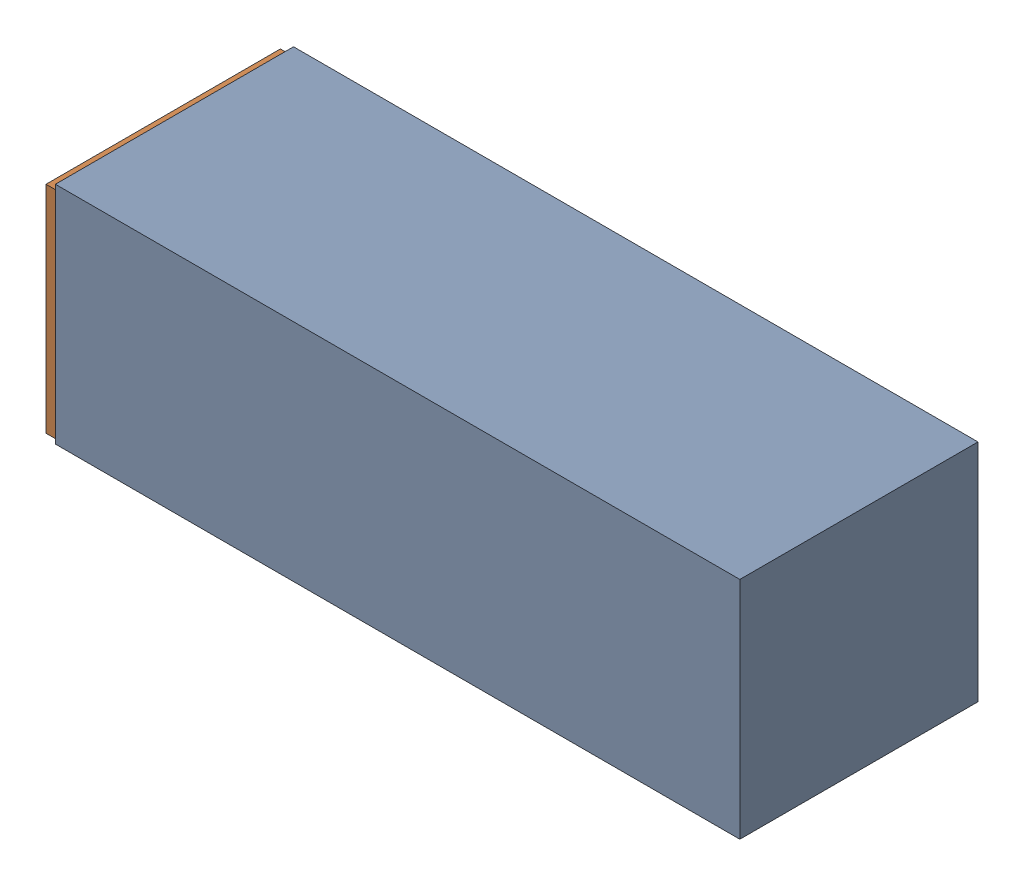
SolidWorks assembly H2, configuration Default. Lengths in mm.
Overall size (46.99 15.24 16.13).
4 component instances, 2 part files, 0 mates.
Components (placement in the parent):
- 407985440-1: 407985440 [Default] at (47.1043 44.5008 -16.5329) size (46.35 15.24 16.13)
  - Extruded_4-1: Extruded_4 [Default] at origin size (46.35 15.24 16.13)
- 407985312-1: 407985312 [Default] at (23.6093 44.5008 -16.2789) size (0.64 14.61 15.88)
  - Extruded_5-1: Extruded_5 [Default] at origin size (0.64 14.61 15.88)
